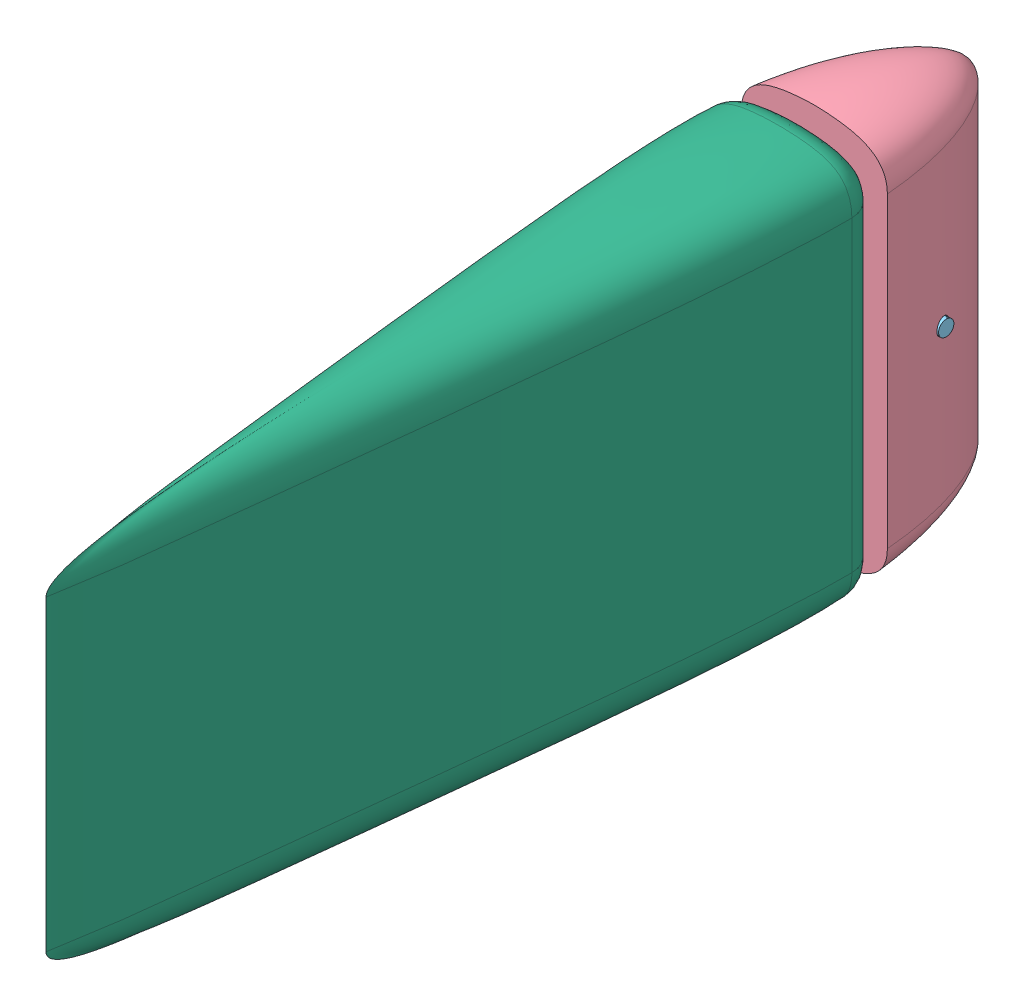
SolidWorks assembly Assemblage Actionneur, configuration Défaut. Lengths in mm.
Overall size (50.48 130.04 301.24).
7 component instances, 6 part files, 14 mates.
Components (placement in the parent):
- Actionneur Aimant-1: Actionneur Aimant [Défaut] at (2.0132 10.4389 83.6242) size (9 71.84 46.4)
- Actionneur bobine-1: Actionneur bobine [Défaut] at (-18.475 34.1787 92.1669) x (0.06643 0 0.997791) z (0.997791 0 -0.06643) size (5.54 85.68 22.54)
- Tige-1: Tige [Défaut] at (-14.5216 48.0078 93.84) x (-0.564159 0 -0.825666) z (0 -1 0) size (3.6 3.6 20)
- Tige-2: Tige [Défaut] at (-0.3456 -27.8655 93.468) x (0.041584 0 0.999135) z (0 -1 0) size (3.6 3.6 20)
- Tête entière-1: Tête entière [Défaut] at (-7.5873 0.4025 32.5889) x (0 0 1) z (0 -1 0) size (301 50.46 129.29)
- Goupille tête actionneur aimant-2: Goupille tête actionneur aimant [Défaut] at (-28.4526 -14.5714 65.6023) x (0 -0.784721 -0.619849) z (1 0 0) size (5 5 42)
- Queue entière-1: Queue entière [Défaut] at (-7.4868 0.0072 32.8242) x (0 0 1) z (0 1 0) size (301 50.31 130)
Mates (geometry in assembly coordinates):
- Coaxiale1: concentric aligned: cylinder of Actionneur Aimant-1 through (-7.4868 27.3745 91.6242) axis (0 1 0) radius 1.8; cylinder of Tige-1 through (-7.4868 28.0078 91.6242) axis (0 1 0) radius 1.8
- Coaxiale2: concentric aligned: cylinder of Actionneur bobine-1 through (-7.4868 -47.5675 91.6242) axis (0 1 0) radius 2; cylinder of Tige-1 through (-7.4868 28.0078 91.6242) axis (0 1 0) radius 1.8
- Coaxiale4: concentric anti-aligned: cylinder of Actionneur bobine-1 through (-7.4868 47.4352 91.6242) axis (0 -1 0) radius 2; cylinder of Tige-2 through (-7.4868 -47.8655 91.6242) axis (0 1 0) radius 1.8
- Verrouiller2: lock: unknown of Actionneur bobine-1; unknown of Tige-1
- Parallèle1: parallel aligned: line of Actionneur Aimant-1 through (-5.0298 31.3745 52.2216) axis (-1 0 0); line of Tête entière-1 through (-4.9397 31.9085 82.5889) axis (-1 0 0)
- Parallèle2: parallel aligned: line of Actionneur Aimant-1 through (-5.0298 34.5405 52.2216) axis (0 -1 0); line of Tête entière-1 through (-31.3497 50.4025 82.5889) axis (0 -1 0)
- Coaxiale7: concentric aligned: cylinder of Actionneur Aimant-1 through (-28.0298 0.4025 60.7889) axis (1 0 0) radius 2.5; cylinder of Tête entière-1 through (-32.8155 0.4025 60.7889) axis (1 0 0) radius 2.6
- Coaxiale9: concentric anti-aligned: cylinder of Tête entière-1 through (-32.8155 0.4025 60.7889) axis (1 0 0) radius 2.6; cylinder of Goupille tête actionneur aimant-2 through (13.5474 0.4025 60.7889) axis (-1 0 0) radius 2.5
- Verrouiller3: lock: unknown of Actionneur Aimant-1; unknown of Tête entière-1
- Verrouiller4: lock: unknown of Tête entière-1; unknown of Goupille tête actionneur aimant-2
- Coaxiale10: concentric aligned: cylinder of Tige-2 through (-7.4868 -47.8655 91.6242) axis (0 1 0) radius 1.8; cylinder of Queue entière-1 through (-7.4868 -48.5437 91.6242) axis (0 1 0) radius 2
- Verrouiller5: lock: unknown of Tige-1; unknown of Queue entière-1
- Verrouiller6: lock: unknown of Tige-2; unknown of Queue entière-1
- Parallèle5: parallel aligned: line of Tête entière-1 through (-7.5873 50.4025 332.5889) axis (0 0 -1); line of Queue entière-1 through (-7.4868 50.0072 332.8242) axis (0 0 -1)
